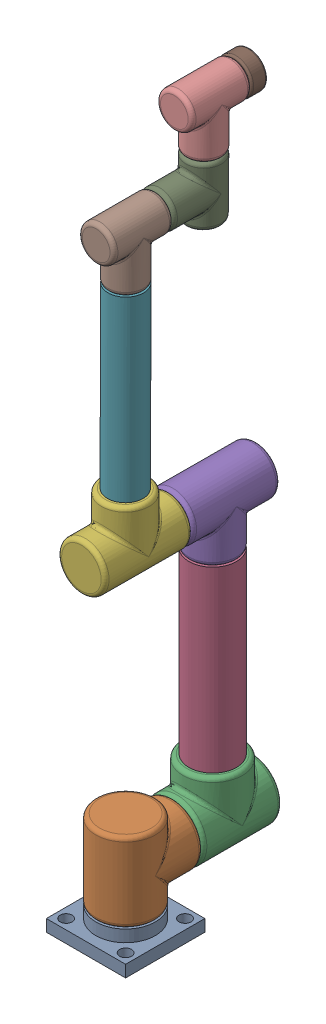
SolidWorks assembly manipulator, configuration Default. Lengths in mm.
Overall size (200 1782.33 440.48).
11 component instances, 7 part files, 22 mates.
Components (placement in the parent):
- M_base-1: M_base [Default] at origin size (200 60 200)
- Motor_150-4: Motor_150 [Default] at (0 60 0) x (-0.000834 0 -1) z (1 0 -0.000834) size (195 200 150.1)
- Motor_150-5: Motor_150 [Default] at (-0.1001 160 -120) x (0 1 0) z (-1 0 0.000834) size (195 200 150.1)
- link_1-1: link_1 [Default] at (-0.1835 280 -219.9999) x (0.012021 0 -0.999928) z (0.999928 0 0.012021) size (120 450 120)
- Motor_120-1: Motor_120 [Default] at (-0.6281 850 -110.0008) x (0 -1 0) z (0.999992 0 0.004042) size (180 220 120.1)
- Motor_120-2: Motor_120 [Default] at (-1.5175 850 109.9974) x (0.002794 0.999996 0.000011) z (-0.999988 0.002794 -0.004042) size (180 220 120.1)
- link_2-1: link_2 [Default] at (-0.7376 969.9995 -0.0004) x (-0.065075 0.000171 0.99788) z (-0.997876 0.002789 -0.065075) size (90 450 90)
- Motor_90-1: Motor_90 [Default] at (0.762 1539.9967 75.006) x (-0.002794 -0.999996 -0.000011) z (0.999995 -0.002794 0.001238) size (165 150 90.1)
- Motor_90-2: Motor_90 [Default] at (0.3121 1465.0029 -194.9953) x (-0.001238 -0.000008 0.999999) z (-0.999945 0.010457 -0.001238) size (165 150 90.1)
- Motor_90-3: Motor_90 [Default] at (2.9277 1734.9888 -119.99) x (-0.010457 -0.999945 -0.000021) z (0.999941 -0.010457 0.002769) size (165 150 90.1)
- end_effector-1: end_effector [Default] at (3.343 1734.9876 -269.9894) x (0.998564 -0.053501 0.002765) z (0.0535 0.998568 0.00014) size (90 40 90)
Mates (geometry in assembly coordinates):
- Coincident20: coordinate: unknown of M_base-1
- Concentric2: concentric anti-aligned: circle of M_base-1; circle of Motor_150-4
- Coincident8: coincident anti-aligned: plane of M_base-1 through (0 60 0) normal (0 1 0); plane of Motor_150-4 through (0 60 0) normal (0 -1 0)
- Coincident9: coincident anti-aligned: circle of Motor_150-4; circle of Motor_150-5
- Coincident10: coincident anti-aligned: plane of Motor_150-5 through (-0.1835 280 -219.9999) normal (0 1 0); plane of link_1-1 through (-0.1835 280 -219.9999) normal (0 -1 0)
- Concentric3: concentric aligned: circle of Motor_150-5; circle of link_1-1
- Lock1: lock: unknown of Motor_150-5; unknown of link_1-1
- Coincident11: coincident anti-aligned: plane of link_1-1 through (-0.1835 730 -219.9999) normal (0 1 0); plane of Motor_120-1 through (-0.1835 730 -219.9999) normal (0 -1 0)
- Concentric4: concentric anti-aligned: circle of link_1-1; circle of Motor_120-1
- Coincident12: coincident anti-aligned: plane of Motor_120-1 through (-0.6281 850 -110.0008) normal (-0.004042 0 0.999992); plane of Motor_120-2 through (-0.6281 850 -110.0008) normal (0.004042 0 -0.999992)
- Concentric5: concentric anti-aligned: circle of Motor_120-1; circle of Motor_120-2
- Coincident14: coincident anti-aligned: plane of Motor_120-2 through (-0.7376 969.9995 -0.0004) normal (0.002794 0.999996 0.000011); plane of link_2-1 through (-0.7376 969.9995 -0.0004) normal (-0.002794 -0.999996 -0.000011)
- Lock3: lock: unknown of Motor_120-2; unknown of link_2-1
- Coincident19: coincident anti-aligned: plane of Motor_90-3 through (3.343 1734.9876 -269.9894) normal (0.002769 -0.000008 -0.999996); plane of end_effector-1 through (3.343 1734.9876 -269.9894) normal (-0.002769 0.000008 0.999996)
- Concentric11: concentric anti-aligned: circle of Motor_90-3; circle of end_effector-1
- Coincident22: coincident anti-aligned: circle of Motor_90-2; circle of Motor_90-3
- Coincident23: coincident anti-aligned: circle of Motor_90-1; circle of Motor_90-2
- Coincident24: coincident anti-aligned: circle of link_2-1; circle of Motor_90-1
- Lock5: lock: unknown of link_1-1; unknown of Motor_120-1
- Lock6: lock: unknown of link_2-1; unknown of Motor_90-1
- Concentric12: concentric anti-aligned: circle of Motor_90-1; circle of Motor_90-2
- Concentric14: concentric anti-aligned: circle of Motor_90-2; circle of Motor_90-3
